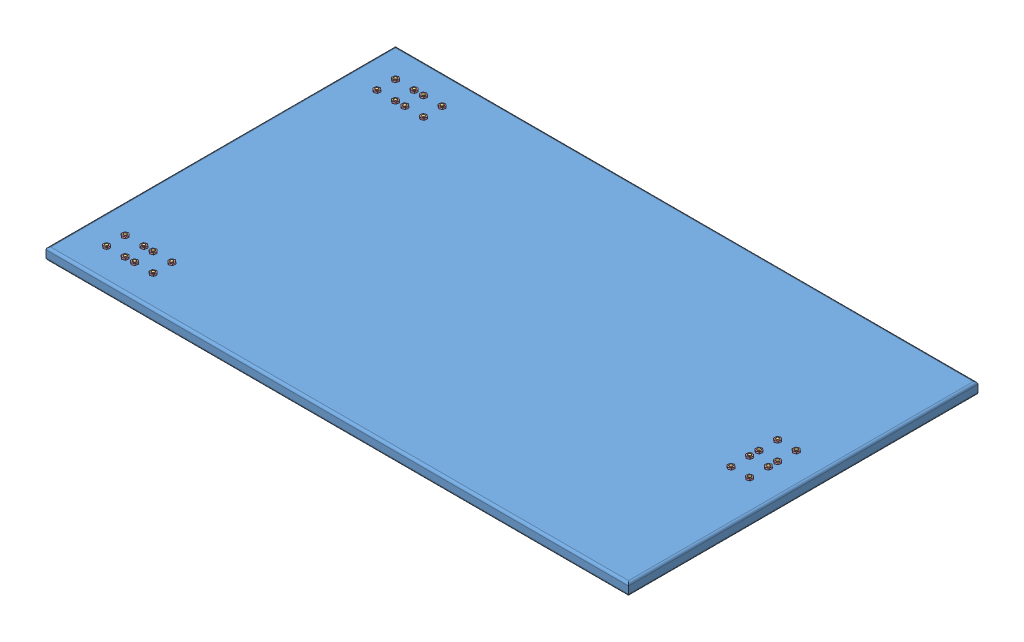
SolidWorks assembly assemblagePlaque, configuration Défaut. Lengths in mm.
Overall size (2500 133.05 1500).
61 component instances, 4 part files, 88 mates.
Components (placement in the parent):
- plaque-1: plaque [Défaut] at (42.7083 65.3445 2500) size (2500 50 1500)
- fixationPlaque-1: fixationPlaque [Défaut] at (1110.4083 29.9622 2320) x (-1 0 0) z (0 0 1) size (120 74.05 120)
  - attachePlaque-1: attachePlaque [Défaut] at (-12.3 -35.3823 120) size (120 74.05 120)
- fixationPlaque-2: fixationPlaque [Défaut] at (1135.0083 29.9622 2680) x (1 0 0) z (0 0 -1) size (120 74.05 120)
  - attachePlaque-1: attachePlaque [Défaut] at (-12.3 -35.3823 120) size (120 74.05 120)
- fixationPlaque-5: fixationPlaque [Défaut] at (-917.2917 29.9622 3067.7) x (0 0 -1) z (-1 0 0) size (120 74.05 120)
  - attachePlaque-1: attachePlaque [Défaut] at (-12.3 -35.3823 120) size (120 74.05 120)
- fixationPlaque-6: fixationPlaque [Défaut] at (-797.2917 29.9622 3067.7) x (0 0 -1) z (-1 0 0) size (120 74.05 120)
  - attachePlaque-1: attachePlaque [Défaut] at (-12.3 -35.3823 120) size (120 74.05 120)
- fixationPlaque-7: fixationPlaque [Défaut] at (-917.2917 29.9622 1907.7) x (0 0 -1) z (-1 0 0) size (120 74.05 120)
  - attachePlaque-1: attachePlaque [Défaut] at (-12.3 -35.3823 120) size (120 74.05 120)
- fixationPlaque-8: fixationPlaque [Défaut] at (-797.2917 29.9622 1907.7) x (0 0 -1) z (-1 0 0) size (120 74.05 120)
  - attachePlaque-1: attachePlaque [Défaut] at (-12.3 -35.3823 120) size (120 74.05 120)
- visPlaque-1: visPlaque [Défaut] at (-1077.2917 52.3445 3120) size (24.69 72 26.25)
- ecrou-1: ecrou [Défaut] at (-1077.2917 115.3445 3120) size (24.81 7 26.32)
- visPlaque-2: visPlaque [Défaut] at (-1077.2917 52.3445 3040) size (24.69 72 26.25)
- visPlaque-3: visPlaque [Défaut] at (-997.2917 52.3445 3120) size (24.69 72 26.25)
- visPlaque-4: visPlaque [Défaut] at (-957.2917 52.3445 3120) size (24.69 72 26.25)
- visPlaque-5: visPlaque [Défaut] at (-997.2917 52.3445 3040) size (24.69 72 26.25)
- visPlaque-7: visPlaque [Défaut] at (-957.2917 52.3445 3040) size (24.69 72 26.25)
- visPlaque-9: visPlaque [Défaut] at (-877.2917 52.3445 3120) size (24.69 72 26.25)
- visPlaque-10: visPlaque [Défaut] at (-877.2917 52.3445 3040) size (24.69 72 26.25)
- visPlaque-11: visPlaque [Défaut] at (-877.2917 52.3445 1880) size (24.69 72 26.25)
- visPlaque-12: visPlaque [Défaut] at (-957.2917 52.3445 1880) size (24.69 72 26.25)
- visPlaque-13: visPlaque [Défaut] at (-877.2917 52.3445 1960) size (24.69 72 26.25)
- visPlaque-14: visPlaque [Défaut] at (-957.2917 52.3445 1960) size (24.69 72 26.25)
- visPlaque-15: visPlaque [Défaut] at (-997.2917 52.3445 1880) size (24.69 72 26.25)
- visPlaque-16: visPlaque [Défaut] at (-1077.2917 52.3445 1960) size (24.69 72 26.25)
- visPlaque-17: visPlaque [Défaut] at (-1077.2917 52.3445 1880) size (24.69 72 26.25)
- visPlaque-18: visPlaque [Défaut] at (-997.2917 52.3445 1960) size (24.69 72 26.25)
- visPlaque-19: visPlaque [Défaut] at (1162.7083 52.3445 2600) size (24.69 72 26.25)
- visPlaque-20: visPlaque [Défaut] at (1082.7083 52.3445 2600) size (24.69 72 26.25)
- visPlaque-21: visPlaque [Défaut] at (1082.7083 52.3445 2520) size (24.69 72 26.25)
- visPlaque-22: visPlaque [Défaut] at (1162.7083 52.3445 2520) size (24.69 72 26.25)
- visPlaque-23: visPlaque [Défaut] at (1162.7083 52.3445 2480) size (24.69 72 26.25)
- visPlaque-25: visPlaque [Défaut] at (1162.7083 52.3445 2400) size (24.69 72 26.25)
- visPlaque-26: visPlaque [Défaut] at (1082.7083 52.3445 2480) size (24.69 72 26.25)
- visPlaque-27: visPlaque [Défaut] at (1082.7083 52.3445 2400) size (24.69 72 26.25)
- ecrou-2: ecrou [Défaut] at (1162.7083 115.3445 2600) size (24.81 7 26.32)
- ecrou-4: ecrou [Défaut] at (1082.7083 115.3445 2600) size (24.81 7 26.32)
- ecrou-5: ecrou [Défaut] at (1082.7083 115.3445 2520) size (24.81 7 26.32)
- ecrou-6: ecrou [Défaut] at (-997.2917 115.3445 3120) size (24.81 7 26.32)
- ecrou-7: ecrou [Défaut] at (-1077.2917 115.3445 3040) size (24.81 7 26.32)
- ecrou-8: ecrou [Défaut] at (-997.2917 115.3445 3040) size (24.81 7 26.32)
- ecrou-9: ecrou [Défaut] at (-957.2917 115.3445 3040) size (24.81 7 26.32)
- ecrou-11: ecrou [Défaut] at (-877.2917 115.3445 3040) size (24.81 7 26.32)
- ecrou-12: ecrou [Défaut] at (-957.2917 115.3445 3120) size (24.81 7 26.32)
- ecrou-13: ecrou [Défaut] at (-877.2917 115.3445 3120) size (24.81 7 26.32)
- ecrou-14: ecrou [Défaut] at (-1077.2917 115.3445 1880) size (24.81 7 26.32)
- ecrou-15: ecrou [Défaut] at (-997.2917 115.3445 1880) size (24.81 7 26.32)
- ecrou-16: ecrou [Défaut] at (-957.2917 115.3445 1880) size (24.81 7 26.32)
- ecrou-17: ecrou [Défaut] at (-1077.2917 115.3445 1960) size (24.81 7 26.32)
- ecrou-18: ecrou [Défaut] at (-997.2917 115.3445 1960) size (24.81 7 26.32)
- ecrou-19: ecrou [Défaut] at (-957.2917 115.3445 1960) size (24.81 7 26.32)
- ecrou-20: ecrou [Défaut] at (-877.2917 115.3445 1960) size (24.81 7 26.32)
- ecrou-21: ecrou [Défaut] at (-877.2917 115.3445 1880) size (24.81 7 26.32)
- ecrou-22: ecrou [Défaut] at (1162.7083 115.3445 2520) size (24.81 7 26.32)
- ecrou-23: ecrou [Défaut] at (1162.7083 115.3445 2480) size (24.81 7 26.32)
- ecrou-24: ecrou [Défaut] at (1082.7083 115.3445 2480) size (24.81 7 26.32)
- ecrou-25: ecrou [Défaut] at (1162.7083 115.3445 2400) size (24.81 7 26.32)
- ecrou-26: ecrou [Défaut] at (1082.7083 115.3445 2400) size (24.81 7 26.32)
Mates (geometry in assembly coordinates):
- Coïncidente1: coincident: circle of plaque-1; circle of fixationPlaque-1/attachePlaque-1
- Coïncidente2: coincident: circle of plaque-1; circle of fixationPlaque-2/attachePlaque-1
- Coïncidente3: coincident: circle of plaque-1; circle of fixationPlaque-1/attachePlaque-1
- Coïncidente4: coincident: circle of plaque-1; circle of fixationPlaque-2/attachePlaque-1
- Coïncidente9: coincident: circle of plaque-1; circle of fixationPlaque-5/attachePlaque-1
- Coïncidente10: coincident: circle of plaque-1; circle of fixationPlaque-5/attachePlaque-1
- Coïncidente11: coincident: circle of plaque-1; circle of fixationPlaque-6/attachePlaque-1
- Coïncidente12: coincident: circle of plaque-1; circle of fixationPlaque-6/attachePlaque-1
- Coïncidente14: coincident: circle of plaque-1; circle of fixationPlaque-7/attachePlaque-1
- Coïncidente15: coincident: circle of plaque-1; circle of fixationPlaque-7/attachePlaque-1
- Coïncidente17: coincident: circle of plaque-1; circle of fixationPlaque-8/attachePlaque-1
- Coïncidente18: coincident: circle of plaque-1; circle of fixationPlaque-8/attachePlaque-1
- Coaxiale1: concentric: cylinder of plaque-1 through (-1077.2917 115.3445 3120) axis (0 -1 0) radius 7.25; cylinder of visPlaque-1 through (-1077.2917 124.3445 3120) axis (0 -1 0) radius 7.25
- Coïncidente19: coincident: plane of fixationPlaque-5/attachePlaque-1 through (-1037.2917 60.3445 3080) normal (0 -1 0); plane of visPlaque-1 through (-1077.2917 60.3445 3120) normal (0 1 0)
- Coïncidente20: coincident: circle of visPlaque-1; circle of ecrou-1
- Coaxiale2: concentric: cylinder of plaque-1 through (-1077.2917 115.3445 3040) axis (0 -1 0) radius 7.25; cylinder of visPlaque-2 through (-1077.2917 124.3445 3040) axis (0 -1 0) radius 7.25
- Coïncidente21: coincident: plane of fixationPlaque-5/attachePlaque-1 through (-1037.2917 60.3445 3080) normal (0 -1 0); plane of visPlaque-2 through (-1077.2917 60.3445 3040) normal (0 1 0)
- Coaxiale3: concentric: cylinder of plaque-1 through (-997.2917 115.3445 3120) axis (0 -1 0) radius 7.25; cylinder of visPlaque-3 through (-997.2917 124.3445 3120) axis (0 -1 0) radius 7.25
- Coaxiale4: concentric: cylinder of plaque-1 through (-957.2917 115.3445 3120) axis (0 -1 0) radius 7.25; cylinder of visPlaque-4 through (-957.2917 124.3445 3120) axis (0 -1 0) radius 7.25
- Coïncidente22: coincident: plane of fixationPlaque-5/attachePlaque-1 through (-1037.2917 60.3445 3080) normal (0 -1 0); plane of visPlaque-3 through (-997.2917 60.3445 3120) normal (0 1 0)
- Coïncidente23: coincident: plane of fixationPlaque-6/attachePlaque-1 through (-917.2917 60.3445 3080) normal (0 -1 0); plane of visPlaque-4 through (-957.2917 60.3445 3120) normal (0 1 0)
- Coaxiale5: concentric: cylinder of plaque-1 through (-997.2917 115.3445 3040) axis (0 -1 0) radius 7.25; cylinder of visPlaque-5 through (-997.2917 124.3445 3040) axis (0 -1 0) radius 7.25
- Coïncidente24: coincident: plane of fixationPlaque-5/attachePlaque-1 through (-1037.2917 60.3445 3080) normal (0 -1 0); plane of visPlaque-5 through (-997.2917 60.3445 3040) normal (0 1 0)
- Coaxiale7: concentric: cylinder of plaque-1 through (-957.2917 115.3445 3040) axis (0 -1 0) radius 7.25; cylinder of visPlaque-7 through (-957.2917 124.3445 3040) axis (0 -1 0) radius 7.25
- Coïncidente26: coincident: plane of fixationPlaque-6/attachePlaque-1 through (-917.2917 60.3445 3080) normal (0 -1 0); plane of visPlaque-7 through (-957.2917 60.3445 3040) normal (0 1 0)
- Coaxiale8: concentric: cylinder of plaque-1 through (-877.2917 115.3445 3120) axis (0 -1 0) radius 7.25; cylinder of visPlaque-9 through (-877.2917 124.3445 3120) axis (0 -1 0) radius 7.25
- Coïncidente27: coincident: plane of fixationPlaque-6/attachePlaque-1 through (-917.2917 60.3445 3080) normal (0 -1 0); plane of visPlaque-9 through (-877.2917 60.3445 3120) normal (0 1 0)
- Coaxiale9: concentric: cylinder of plaque-1 through (-877.2917 115.3445 3040) axis (0 -1 0) radius 7.25; cylinder of visPlaque-10 through (-877.2917 124.3445 3040) axis (0 -1 0) radius 7.25
- Coïncidente28: coincident: plane of fixationPlaque-6/attachePlaque-1 through (-917.2917 60.3445 3080) normal (0 -1 0); plane of visPlaque-10 through (-877.2917 60.3445 3040) normal (0 1 0)
- Coaxiale10: concentric: cylinder of plaque-1 through (-877.2917 115.3445 1880) axis (0 -1 0) radius 7.25; cylinder of visPlaque-11 through (-877.2917 124.3445 1880) axis (0 -1 0) radius 7.25
- Coïncidente29: coincident: plane of fixationPlaque-8/attachePlaque-1 through (-917.2917 60.3445 1920) normal (0 -1 0); plane of visPlaque-11 through (-877.2917 60.3445 1880) normal (0 1 0)
- Coaxiale11: concentric: cylinder of plaque-1 through (-957.2917 115.3445 1880) axis (0 -1 0) radius 7.25; cylinder of visPlaque-12 through (-957.2917 124.3445 1880) axis (0 -1 0) radius 7.25
- Coïncidente30: coincident: plane of fixationPlaque-8/attachePlaque-1 through (-917.2917 60.3445 1920) normal (0 -1 0); plane of visPlaque-12 through (-957.2917 60.3445 1880) normal (0 1 0)
- Coaxiale12: concentric: cylinder of plaque-1 through (-877.2917 115.3445 1960) axis (0 -1 0) radius 7.25; cylinder of visPlaque-13 through (-877.2917 124.3445 1960) axis (0 -1 0) radius 7.25
- Coïncidente31: coincident: plane of fixationPlaque-8/attachePlaque-1 through (-917.2917 60.3445 1920) normal (0 -1 0); plane of visPlaque-13 through (-877.2917 60.3445 1960) normal (0 1 0)
- Coaxiale13: concentric: cylinder of plaque-1 through (-957.2917 115.3445 1960) axis (0 -1 0) radius 7.25; cylinder of visPlaque-14 through (-957.2917 124.3445 1960) axis (0 -1 0) radius 7.25
- Coïncidente32: coincident: plane of fixationPlaque-8/attachePlaque-1 through (-917.2917 60.3445 1920) normal (0 -1 0); plane of visPlaque-14 through (-957.2917 60.3445 1960) normal (0 1 0)
- Coaxiale14: concentric: cylinder of plaque-1 through (-997.2917 115.3445 1880) axis (0 -1 0) radius 7.25; cylinder of visPlaque-15 through (-997.2917 124.3445 1880) axis (0 -1 0) radius 7.25
- Coïncidente33: coincident: plane of fixationPlaque-7/attachePlaque-1 through (-1037.2917 60.3445 1920) normal (0 -1 0); plane of visPlaque-15 through (-997.2917 60.3445 1880) normal (0 1 0)
- Coaxiale15: concentric: cylinder of plaque-1 through (-1077.2917 115.3445 1960) axis (0 -1 0) radius 7.25; cylinder of visPlaque-16 through (-1077.2917 124.3445 1960) axis (0 -1 0) radius 7.25
- Coïncidente34: coincident: plane of fixationPlaque-7/attachePlaque-1 through (-1037.2917 60.3445 1920) normal (0 -1 0); plane of visPlaque-16 through (-1077.2917 60.3445 1960) normal (0 1 0)
- Coaxiale16: concentric: cylinder of plaque-1 through (-1077.2917 115.3445 1880) axis (0 -1 0) radius 7.25; cylinder of visPlaque-17 through (-1077.2917 124.3445 1880) axis (0 -1 0) radius 7.25
- Coïncidente35: coincident: plane of fixationPlaque-7/attachePlaque-1 through (-1037.2917 60.3445 1920) normal (0 -1 0); plane of visPlaque-17 through (-1077.2917 60.3445 1880) normal (0 1 0)
- Coaxiale17: concentric: cylinder of plaque-1 through (-997.2917 115.3445 1960) axis (0 -1 0) radius 7.25; cylinder of visPlaque-18 through (-997.2917 124.3445 1960) axis (0 -1 0) radius 7.25
- Coïncidente36: coincident: plane of fixationPlaque-7/attachePlaque-1 through (-1037.2917 60.3445 1920) normal (0 -1 0); plane of visPlaque-18 through (-997.2917 60.3445 1960) normal (0 1 0)
- Coaxiale18: concentric: cylinder of plaque-1 through (1162.7083 115.3445 2600) axis (0 -1 0) radius 7.25; cylinder of visPlaque-19 through (1162.7083 124.3445 2600) axis (0 -1 0) radius 7.25
- Coïncidente37: coincident: plane of fixationPlaque-2/attachePlaque-1 through (1122.7083 60.3445 2560) normal (0 -1 0); plane of visPlaque-19 through (1162.7083 60.3445 2600) normal (0 1 0)
- Coaxiale19: concentric: cylinder of plaque-1 through (1082.7083 115.3445 2600) axis (0 -1 0) radius 7.25; cylinder of visPlaque-20 through (1082.7083 124.3445 2600) axis (0 -1 0) radius 7.25
- Coïncidente38: coincident: plane of fixationPlaque-2/attachePlaque-1 through (1122.7083 60.3445 2560) normal (0 -1 0); plane of visPlaque-20 through (1082.7083 60.3445 2600) normal (0 1 0)
- Coaxiale20: concentric: cylinder of plaque-1 through (1082.7083 115.3445 2520) axis (0 -1 0) radius 7.25; cylinder of visPlaque-21 through (1082.7083 124.3445 2520) axis (0 -1 0) radius 7.25
- Coïncidente39: coincident: plane of fixationPlaque-2/attachePlaque-1 through (1122.7083 60.3445 2560) normal (0 -1 0); plane of visPlaque-21 through (1082.7083 60.3445 2520) normal (0 1 0)
- Coaxiale21: concentric: cylinder of plaque-1 through (1162.7083 115.3445 2520) axis (0 -1 0) radius 7.25; cylinder of visPlaque-22 through (1162.7083 124.3445 2520) axis (0 -1 0) radius 7.25
- Coïncidente40: coincident: plane of fixationPlaque-2/attachePlaque-1 through (1122.7083 60.3445 2560) normal (0 -1 0); plane of visPlaque-22 through (1162.7083 60.3445 2520) normal (0 1 0)
- Coaxiale22: concentric: cylinder of plaque-1 through (1162.7083 115.3445 2480) axis (0 -1 0) radius 7.25; cylinder of visPlaque-23 through (1162.7083 124.3445 2480) axis (0 -1 0) radius 7.25
- Coïncidente41: coincident: plane of fixationPlaque-1/attachePlaque-1 through (1122.7083 60.3445 2440) normal (0 -1 0); plane of visPlaque-23 through (1162.7083 60.3445 2480) normal (0 1 0)
- Coaxiale24: concentric: cylinder of plaque-1 through (1162.7083 115.3445 2400) axis (0 -1 0) radius 7.25; cylinder of visPlaque-25 through (1162.7083 124.3445 2400) axis (0 -1 0) radius 7.25
- Coïncidente42: coincident: plane of fixationPlaque-1/attachePlaque-1 through (1122.7083 60.3445 2440) normal (0 -1 0); plane of visPlaque-25 through (1162.7083 60.3445 2400) normal (0 1 0)
- Coaxiale25: concentric: cylinder of plaque-1 through (1082.7083 115.3445 2480) axis (0 -1 0) radius 7.25; cylinder of visPlaque-26 through (1082.7083 124.3445 2480) axis (0 -1 0) radius 7.25
- Coïncidente43: coincident: plane of fixationPlaque-1/attachePlaque-1 through (1122.7083 60.3445 2440) normal (0 -1 0); plane of visPlaque-26 through (1082.7083 60.3445 2480) normal (0 1 0)
- Coaxiale26: concentric: cylinder of plaque-1 through (1082.7083 115.3445 2400) axis (0 -1 0) radius 7.25; cylinder of visPlaque-27 through (1082.7083 124.3445 2400) axis (0 -1 0) radius 7.25
- Coïncidente44: coincident: plane of fixationPlaque-1/attachePlaque-1 through (1122.7083 60.3445 2440) normal (0 -1 0); plane of visPlaque-27 through (1082.7083 60.3445 2400) normal (0 1 0)
- Coaxiale29: concentric: cylinder of visPlaque-19 through (1162.7083 124.3445 2600) axis (0 -1 0) radius 7.25; cylinder of ecrou-2 through (1162.7083 115.3445 2600) axis (0 1 0) radius 7.25
- Coïncidente46: coincident: plane of plaque-1 through (42.7083 115.3445 2500) normal (0 1 0); plane of ecrou-2 through (1162.7083 115.3445 2600) normal (0 -1 0)
- Coaxiale30: concentric: cylinder of visPlaque-20 through (1082.7083 124.3445 2600) axis (0 -1 0) radius 7.25; cylinder of ecrou-4 through (1082.7083 115.3445 2600) axis (0 1 0) radius 7.25
- Coïncidente47: coincident: plane of plaque-1 through (42.7083 115.3445 2500) normal (0 1 0); plane of ecrou-4 through (1082.7083 115.3445 2600) normal (0 -1 0)
- Coaxiale31: concentric: cylinder of visPlaque-21 through (1082.7083 124.3445 2520) axis (0 -1 0) radius 7.25; cylinder of ecrou-5 through (1082.7083 115.3445 2520) axis (0 1 0) radius 7.25
- Coïncidente48: coincident: plane of plaque-1 through (42.7083 115.3445 2500) normal (0 1 0); plane of ecrou-5 through (1082.7083 115.3445 2520) normal (0 -1 0)
- Coïncidente50: coincident: plane of plaque-1 through (42.7083 115.3445 2500) normal (0 1 0); plane of ecrou-6 through (-997.2917 115.3445 3120) normal (0 -1 0)
- Coïncidente51: coincident: plane of plaque-1 through (42.7083 115.3445 2500) normal (0 1 0); plane of ecrou-7 through (-1077.2917 115.3445 3040) normal (0 -1 0)
- Coïncidente52: coincident: circle of visPlaque-2; cylinder of ecrou-7 through (-1077.2917 115.3445 3040) axis (0 1 0) radius 7.25
- Coïncidente53: coincident: circle of visPlaque-5; circle of ecrou-8
- Coïncidente54: coincident: circle of visPlaque-7; circle of ecrou-9
- Coïncidente56: coincident: circle of visPlaque-10; circle of ecrou-11
- Coïncidente57: coincident: circle of visPlaque-4; circle of ecrou-12
- Coïncidente58: coincident: circle of visPlaque-9; circle of ecrou-13
- Coïncidente59: coincident: circle of visPlaque-17; circle of ecrou-14
- Coïncidente60: coincident: circle of visPlaque-15; circle of ecrou-15
- Coïncidente61: coincident: circle of visPlaque-12; circle of ecrou-16
- Coïncidente62: coincident: circle of visPlaque-16; circle of ecrou-17
- Coïncidente63: coincident: circle of visPlaque-18; circle of ecrou-18
- Coïncidente64: coincident: circle of visPlaque-14; circle of ecrou-19
- Coïncidente65: coincident: circle of visPlaque-13; circle of ecrou-20
- Coïncidente66: coincident: circle of visPlaque-11; circle of ecrou-21
- Coïncidente67: coincident: circle of visPlaque-22; circle of ecrou-22
- Coïncidente68: coincident: circle of visPlaque-23; circle of ecrou-23
- Coïncidente69: coincident: circle of visPlaque-26; circle of ecrou-24
- Coïncidente70: coincident: circle of visPlaque-25; circle of ecrou-25
- Coïncidente71: coincident: circle of visPlaque-27; circle of ecrou-26
